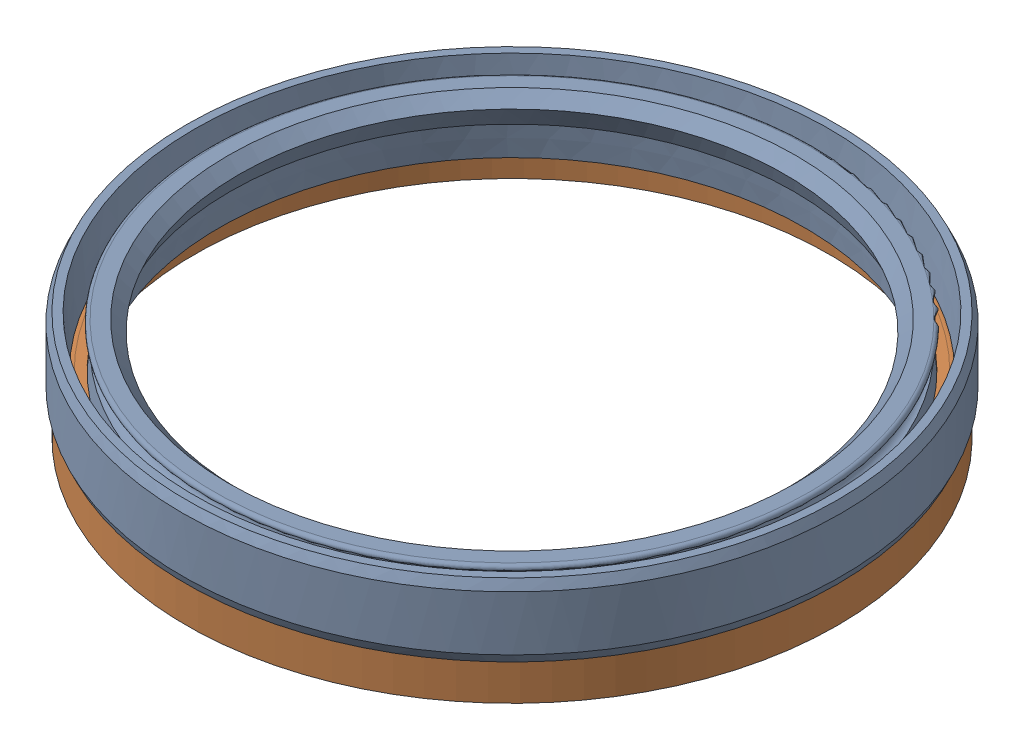
SolidWorks assembly b90x110x12_gb9877_1_1, configuration 默认. Lengths in mm.
Overall size (108.6 17.9 108.6).
2 component instances, 2 part files, 0 mates.
Components (placement in the parent):
- b90x110x12_gb9877_1_rubber_1-1: b90x110x12_gb9877_1_rubber_1 [默认] at origin size (108.6 12 108.6)
- b90x110x12_gb9877_1_frame_1-1: b90x110x12_gb9877_1_frame_1 [默认] at (0 -2.4 0) x (-1 0 0) z (0 0 1) size (107.2 9.5 107.2)
